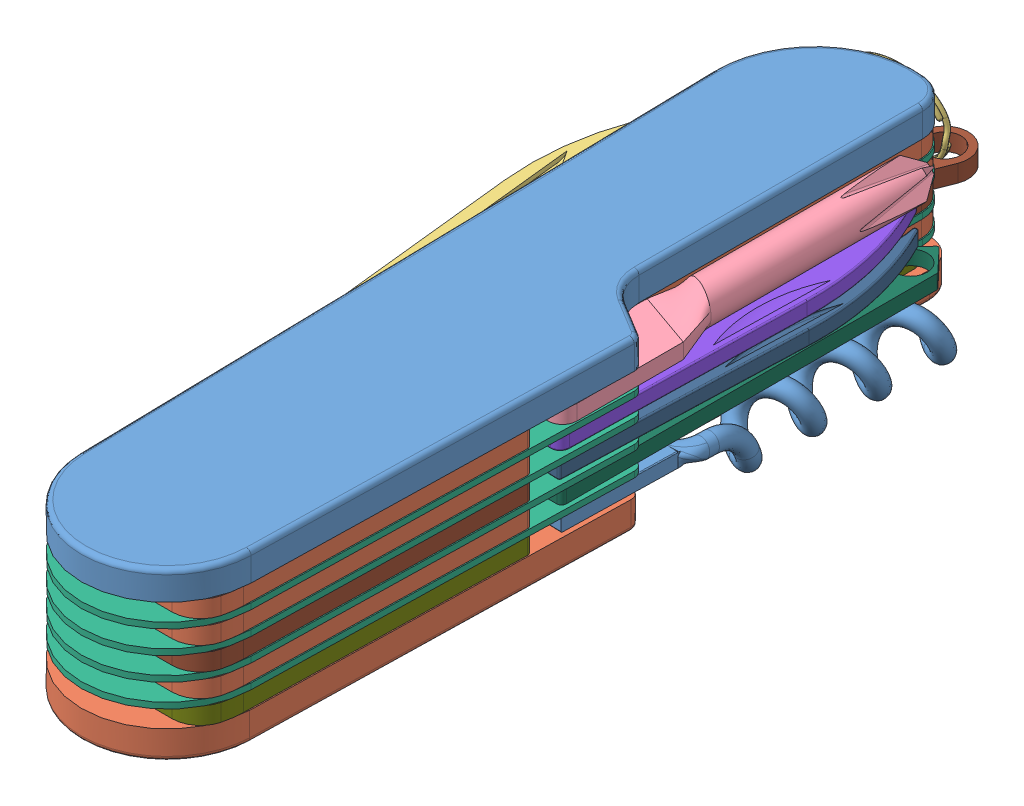
SolidWorks assembly PocketKnifeAssem, configuration Default. Lengths in mm.
Overall size (29.23 19.28 92.52).
29 component instances, 21 part files, 73 mates.
Components (placement in the parent):
- cover-1: cover [Default] at (42.4795 -100.7899 21.8266) size (20.34 3 87.48)
- small_plate2-1: small_plate2 [Default] at (33.7389 -100.7899 -56.4961) x (1 0 0) z (0 -1 0) size (18.24 83.5 1.8)
- BigKnife-1: BigKnife [Default] at (33.6183 -101.5899 24.7252) x (0.994522 0 -0.104528) z (0 1 0) size (12.5 72.88 1.71)
- philips-1: philips [Default] at (49.8425 -100.3899 -50.8894) x (0 0 1) z (-1 0 0) size (41 4.02 5.91)
- pin-1: pin [Default] at (49.2494 -106.6899 -13.3894) x (0.810621 0 0.585571) z (0 -1 0) size (2 2 15.8)
- pin-2: pin [Default] at (39.7745 -106.6899 20.1566) x (0.663596 0 -0.748091) z (0 -1 0) size (2 2 15.8)
- pin-3: pin [Default] at (37.0805 -106.6899 -47.79) x (0.663596 0 -0.748091) z (0 -1 0) size (2 2 15.8)
- plateyall-1: plateyall [Default] at (42.4795 -103.2149 21.8266) size (20.34 0.62 87.48)
- saw-1: saw [Default] at (33.7111 -104.8149 24.7649) x (0.991886 0 -0.12713) z (0.12713 0 0.991886) size (11.09 3.22 73.69)
- reamer -1: reamer  [Default] at (45.7749 -103.2149 -10.0144) x (0.021815 0 -0.999762) z (0 -1 0) size (40.75 6.2 2.29)
- small_plate2-3: small_plate2 [Default] at (33.7389 -103.2149 -56.4961) x (1 0 0) z (0 -1 0) size (18.24 83.5 1.8)
- sawknife-1: sawknife [Default] at (32.0153 -107.1399 28.3905) x (0.99956 0 -0.029666) z (0.029666 0 0.99956) size (11.83 1.5 73.8)
- NailPolisher -1: NailPolisher  [Default] at (45.932 -105.6399 -10.0832) x (0.034899 0 -0.999391) z (0 -1 0) size (40.08 6.02 1.67)
- plateyall-2: plateyall [Default] at (42.4795 -105.6399 21.8266) size (20.34 0.62 87.48)
- plateyall-3: plateyall [Default] at (42.4795 -108.0649 21.8266) size (20.34 0.62 87.48)
- small_plate2-5: small_plate2 [Default] at (33.7389 -108.0649 -56.4961) x (1 0 0) z (0 -1 0) size (18.24 83.5 1.8)
- small_plate3-1: small_plate3 [Default] at (33.7389 -105.6399 -56.4961) x (1 0 0) z (0 -1 0) size (18.24 88.5 1.8)
- scissors-1: scissors [Default] at (33.6478 -108.8649 24.7079) x (0.996195 0 -0.087156) z (0.087156 0 0.996195) size (17.57 1.82 73.9)
  - scissors1-1: scissors1 [Default] at origin size (12.84 1.82 73.9)
  - tensed_spring-1: tensed_spring [Default] at (15.3791 -0.8 -13.3543) x (0.992407 0 -0.123) z (0 1 0) size (4.32 13.19 1.6)
  - scissor arm2-1: scissor arm2 [Default] at (15.5396 -0.8 -22.5845) x (0.985924 0 -0.167194) z (0.167194 0 0.985924) size (9 1.6 52)
- bender-1: bender [Default] at (46.0494 -108.0649 -9.9894) x (0 0 -1) z (0 -1 0) size (41.91 6 1.5)
- plateyall-4: plateyall [Default] at (42.4795 -110.4899 21.8266) size (20.34 0.62 87.48)
- small_plate1-1: small_plate1 [Default] at (33.7389 -110.4899 -56.4961) x (1 0 0) z (0 -1 0) size (8.24 80.41 1.8)
- BottleOpener-1: BottleOpener [Default] at (29.3171 -110.4899 -52.687) x (0.998732 0 0.050339) z (0.050339 0 -0.998732) size (15.07 1.63 37)
- CanOpener-1: CanOpener [Default] at (33.9411 -112.0899 24.8773) x (0.987688 0 -0.156434) z (0.156434 0 0.987688) size (12.6 3.13 35.76)
- MainBottleOpener-1: MainBottleOpener [Default] at (50.1781 -113.7399 -30.7399) x (0.999762 0 0.021815) z (-0.021815 0 0.999762) size (7.09 6.91 42)
- cover_up-1: cover_up [Default] at (42.4795 -112.2899 21.8266) x (-0.999762 0 -0.021815) z (-0.021815 0 0.999762) size (20.97 3 87.58)
- holder-1: holder [Default] at (38.6408 -104.5344 -57.3996) x (-0.031611 -0.983832 -0.176284) z (0.9843 0 -0.176502) size (10.5 1.02 10.5)
Mates (geometry in assembly coordinates):
- Coincident1: coincident: plane of cover-1 through (42.4795 -100.7899 21.8266) normal (0 -1 0); plane of small_plate2-1 through (43.3489 -100.7899 -43.9848) normal (0 1 0)
- Parallel1: parallel: plane of cover-1 through (46.3489 -97.7899 -55.9166) normal (1 0 0); plane of small_plate2-1 through (46.2389 -102.5899 -24.3461) normal (1 0 0)
- Concentric1: concentric: cylinder of cover-1 through (43.3489 -97.7899 -53.6061) axis (0 -1 0) radius 3; cylinder of small_plate2-1 through (43.3489 -102.5899 -53.6061) axis (0 1 0) radius 2.89
- Concentric2: concentric: cylinder of cover-1 through (49.2494 -98.7899 -13.3894) axis (0 -1 0) radius 1; cylinder of pin-1 through (49.2494 -114.5899 -13.3894) axis (0 1 0) radius 1
- Coincident3: coincident: plane of cover-1 through (49.2494 -98.7899 -13.3894) normal (0 -1 0); circle of pin-1
- Concentric3: concentric: cylinder of cover-1 through (39.7745 -98.7899 20.1566) axis (0 -1 0) radius 1; cylinder of pin-2 through (39.7745 -114.5899 20.1566) axis (0 1 0) radius 1
- Coincident4: coincident: plane of cover-1 through (39.7745 -98.7899 20.1566) normal (0 -1 0); plane of pin-2 through (39.7745 -98.7899 20.1566) normal (0 1 0)
- Concentric4: concentric: cylinder of cover-1 through (37.0805 -98.7899 -47.79) axis (0 -1 0) radius 1; cylinder of pin-3 through (37.0805 -114.5899 -47.79) axis (0 1 0) radius 1
- Coincident5: coincident: plane of cover-1 through (37.0805 -98.7899 -47.79) normal (0 -1 0); plane of pin-3 through (37.0805 -98.7899 -47.79) normal (0 1 0)
- Concentric5: concentric: circle of BigKnife-1; cylinder of pin-2 through (39.7745 -114.5899 20.1566) axis (0 1 0) radius 1
- Coincident6: coincident: plane of cover-1 through (42.4795 -100.7899 21.8266) normal (0 -1 0); plane of BigKnife-1 through (33.6183 -100.7899 24.7252) normal (0 1 0)
- LimitAngle1: limit planar angle = 0.10472 rad: plane of BigKnife-1 through (36.6019 -102.3968 24.4116) normal (-0.994522 0 0.104528); plane of small_plate2-1 through (43.7389 -102.5899 -41.9961) normal (-1 0 0)
- Concentric6: concentric: cylinder of philips-1 through (49.2494 -92.3899 -13.3894) axis (0 -1 0) radius 1; cylinder of pin-1 through (49.2494 -114.5899 -13.3894) axis (0 1 0) radius 1
- Coincident8: coincident: plane of cover-1 through (42.4795 -100.7899 21.8266) normal (0 -1 0); plane of philips-1 through (49.8425 -100.7899 -50.8894) normal (0 1 0)
- LimitAngle2: limit planar angle = 0 rad: plane of philips-1 through (46.3975 -100.3899 -50.8894) normal (-1 0 0); plane of small_plate2-1 through (46.2389 -102.5899 -24.3461) normal (1 0 0)
- Concentric12: concentric: cylinder of cover-1 through (43.3489 -97.7899 -53.6061) axis (0 -1 0) radius 3; cylinder of plateyall-1 through (43.3489 -102.5899 -53.6061) axis (0 -1 0) radius 3
- Coincident14: coincident: plane of small_plate2-1 through (43.3489 -102.5899 -43.9848) normal (0 -1 0); plane of plateyall-1 through (42.4795 -102.5899 21.8266) normal (0 1 0)
- Coincident16: coincident: plane of plateyall-1 through (42.4795 -103.2149 21.8266) normal (0 -1 0); plane of small_plate2-3 through (43.3489 -103.2149 -43.9848) normal (0 1 0)
- Concentric13: concentric: cylinder of small_plate2-1 through (43.3489 -102.5899 -53.6061) axis (0 1 0) radius 2.89; cylinder of small_plate2-3 through (43.3489 -105.0149 -53.6061) axis (0 1 0) radius 2.89
- Concentric14: concentric: cylinder of small_plate2-1 through (48.1532 -102.5899 24.0039) axis (0 1 0) radius 3; cylinder of small_plate2-3 through (48.1532 -105.0149 24.0039) axis (0 1 0) radius 3
- Concentric15: concentric: cylinder of pin-2 through (39.7745 -114.5899 20.1566) axis (0 1 0) radius 1; cylinder of saw-1 through (39.7745 -103.2149 20.1566) axis (0 -1 0) radius 1
- Coincident17: coincident: plane of plateyall-1 through (42.4795 -103.2149 21.8266) normal (0 -1 0); plane of saw-1 through (42.0288 -103.2149 -39.8885) normal (0 1 0)
- LimitAngle3: limit planar angle = 0.050044 rad: plane of small_plate2-3 through (43.7389 -105.0149 -41.9961) normal (-1 0 0); plane of saw-1 through (32.9483 -103.2149 18.8136) normal (-0.998748 0 0.050023)
- Concentric16: concentric: cylinder of pin-1 through (49.2494 -114.5899 -13.3894) axis (0 1 0) radius 1; cylinder of reamer -1 through (49.2494 -104.8149 -13.3894) axis (0 1 0) radius 1
- Coincident19: coincident: plane of plateyall-1 through (42.4795 -103.2149 21.8266) normal (0 -1 0); plane of reamer -1 through (22.5351 -103.2149 -35.9444) normal (0 1 0)
- LimitAngle4: limit planar angle = 3.141593 rad: plane of reamer -1 through (51.9735 -104.8149 -9.8791) normal (0.999762 0 0.021815); plane of small_plate2-3 through (51.9889 -105.0149 -6.9961) normal (0.999762 0 0.021815)
- Concentric18: concentric: cylinder of pin-3 through (37.0805 -114.5899 -47.79) axis (0 1 0) radius 1; cylinder of plateyall-2 through (37.0805 -105.0139 -47.79) axis (0 -1 0) radius 1
- Concentric19: concentric: cylinder of pin-1 through (49.2494 -114.5899 -13.3894) axis (0 1 0) radius 1; cylinder of plateyall-2 through (49.2494 -105.0139 -13.3894) axis (0 -1 0) radius 1
- Coincident22: coincident: plane of small_plate2-3 through (43.3489 -105.0149 -43.9848) normal (0 -1 0); plane of plateyall-2 through (42.4795 -105.0149 21.8266) normal (0 1 0)
- Concentric23: concentric: cylinder of pin-1 through (49.2494 -114.5899 -13.3894) axis (0 1 0) radius 1; cylinder of NailPolisher -1 through (49.2494 -105.6399 -13.3894) axis (0 -1 0) radius 1
- Coincident28: coincident: plane of NailPolisher -1 through (22.8309 -105.6399 -36.2436) normal (0 1 0); plane of plateyall-2 through (42.4795 -105.6399 21.8266) normal (0 -1 0)
- Concentric24: concentric: cylinder of pin-3 through (37.0805 -114.5899 -47.79) axis (0 1 0) radius 1; cylinder of plateyall-3 through (37.0805 -107.4389 -47.79) axis (0 -1 0) radius 1
- Concentric25: concentric: cylinder of pin-2 through (39.7745 -114.5899 20.1566) axis (0 1 0) radius 1; cylinder of plateyall-3 through (39.7745 -107.4389 20.1566) axis (0 -1 0) radius 1
- Coincident33: coincident: plane of plateyall-2 through (42.4795 -105.6399 21.8266) normal (0 -1 0); plane of small_plate3-1 through (43.3489 -105.6399 -43.9848) normal (0 1 0)
- Concentric28: concentric: cylinder of small_plate2-3 through (48.1532 -105.0149 24.0039) axis (0 1 0) radius 3; cylinder of small_plate3-1 through (48.1532 -107.4399 24.0039) axis (0 1 0) radius 3
- Concentric29: concentric: cylinder of small_plate2-3 through (43.3489 -105.0149 -53.6061) axis (0 1 0) radius 2.89; cylinder of small_plate3-1 through (43.3489 -107.4399 -53.6061) axis (0 1 0) radius 2.89
- Coincident34: coincident: plane of plateyall-3 through (42.4795 -108.0649 21.8266) normal (0 -1 0); plane of small_plate2-5 through (43.3489 -108.0649 -43.9848) normal (0 1 0)
- Concentric30: concentric: cylinder of small_plate2-5 through (48.1532 -109.8649 24.0039) axis (0 1 0) radius 3; cylinder of small_plate3-1 through (48.1532 -107.4399 24.0039) axis (0 1 0) radius 3
- LimitAngle7: limit planar angle = 0.034907 rad: plane of NailPolisher -1 through (51.9283 -107.2399 -9.8738) normal (0.999391 0 0.034899); plane of small_plate3-1 through (46.2389 -107.4399 -24.3461) normal (1 0 0)
- Concentric31: concentric: cylinder of pin-2 through (39.7745 -114.5899 20.1566) axis (0 1 0) radius 1; cylinder of sawknife-1 through (39.7745 -105.6399 20.1566) axis (0 -1 0) radius 1
- Coincident36: coincident: plane of sawknife-1 through (32.0153 -105.6399 28.3905) normal (0 1 0); plane of plateyall-2 through (42.4795 -105.6399 21.8266) normal (0 -1 0)
- LimitAngle9: limit planar angle = 0.029671 rad: plane of sawknife-1 through (35.7714 -107.2399 13.3724) normal (-0.99956 0 0.029666); plane of small_plate3-1 through (43.7389 -107.4399 -41.9961) normal (-1 0 0)
- Concentric32: concentric: cylinder of pin-2 through (39.7745 -114.5899 20.1566) axis (0 1 0) radius 1; cylinder of scissors-1/scissors1-1 through (39.7745 -109.6649 20.1566) axis (0 1 0) radius 1
- Coincident38: coincident: plane of plateyall-3 through (42.4795 -108.0649 21.8266) normal (0 -1 0); plane of scissors-1/scissors1-1 through (33.7494 -108.0649 -15.5676) normal (0 1 0)
- Concentric33: concentric: cylinder of small_plate2-3 through (43.3489 -105.0149 -53.6061) axis (0 1 0) radius 2.89; cylinder of small_plate2-5 through (43.3489 -109.8649 -53.6061) axis (0 1 0) radius 2.89
- LimitAngle10: limit planar angle = 0.087266 rad: plane of small_plate2-5 through (43.7389 -109.8649 -41.9961) normal (-1 0 0); plane of scissors-1/scissors1-1 through (36.6364 -109.6649 24.4465) normal (-0.996195 0 0.087156)
- Concentric34: concentric: cylinder of pin-1 through (49.2494 -114.5899 -13.3894) axis (0 1 0) radius 1; cylinder of bender-1 through (49.2494 -108.0649 -13.3894) axis (0 -1 0) radius 1
- Coincident43: coincident: plane of plateyall-3 through (42.4795 -108.0649 21.8266) normal (0 -1 0); plane of bender-1 through (46.0494 -108.0649 -9.9894) normal (0 1 0)
- LimitAngle11: limit planar angle = 0 rad: plane of bender-1 through (52.0494 -109.5649 -9.9894) normal (1 0 0); plane of small_plate2-5 through (46.2389 -109.8649 -24.3461) normal (1 0 0)
- Concentric35: concentric: cylinder of pin-2 through (39.7745 -114.5899 20.1566) axis (0 1 0) radius 1; cylinder of plateyall-4 through (39.7745 -109.8639 20.1566) axis (0 -1 0) radius 1
- Concentric36: concentric: cylinder of pin-3 through (37.0805 -114.5899 -47.79) axis (0 1 0) radius 1; circle of plateyall-4
- Coincident46: coincident: plane of small_plate2-5 through (43.3489 -109.8649 -43.9848) normal (0 -1 0); plane of plateyall-4 through (42.4795 -109.8649 21.8266) normal (0 1 0)
- Concentric37: concentric: cylinder of pin-1 through (49.2494 -114.5899 -13.3894) axis (0 1 0) radius 1; cylinder of MainBottleOpener-1 through (49.2494 -117.0391 -13.3894) axis (0 1 0) radius 1
- Coincident47: coincident: plane of plateyall-4 through (42.4795 -110.4899 21.8266) normal (0 -1 0); plane of MainBottleOpener-1 through (50.1781 -110.4899 -30.7399) normal (0 1 0)
- Coincident48: coincident: plane of plateyall-4 through (42.4795 -110.4899 21.8266) normal (0 -1 0); plane of small_plate1-1 through (43.3489 -110.4899 -43.9848) normal (0 1 0)
- Concentric38: concentric: cylinder of small_plate2-5 through (48.1532 -109.8649 24.0039) axis (0 1 0) radius 3; cylinder of small_plate1-1 through (48.1532 -112.2899 24.0039) axis (0 1 0) radius 3
- Parallel16: parallel: plane of small_plate2-5 through (51.9889 -109.8649 -6.9961) normal (0.999762 0 0.021815); plane of small_plate1-1 through (51.9889 -112.2899 -6.9961) normal (0.999762 0 0.021815)
- Concentric39: concentric: cylinder of pin-2 through (39.7745 -114.5899 20.1566) axis (0 1 0) radius 1; cylinder of CanOpener-1 through (39.7745 -112.0899 20.1566) axis (0 1 0) radius 1
- Coincident50: coincident: plane of plateyall-4 through (42.4795 -110.4899 21.8266) normal (0 -1 0); plane of CanOpener-1 through (46.5346 -110.4899 1.9247) normal (0 1 0)
- LimitAngle12: limit planar angle = 2.984513 rad: plane of CanOpener-1 through (33.9411 -110.4899 24.8773) normal (-0.987688 0 0.156434); plane of small_plate1-1 through (43.7389 -112.2899 -41.9961) normal (-1 0 0)
- LimitAngle13: limit planar angle = 3.141593 rad: plane of MainBottleOpener-1 through (52.2385 -111.9899 -22.0262) normal (0.999762 0 0.021815); plane of small_plate1-1 through (51.9889 -112.2899 -6.9961) normal (0.999762 0 0.021815)
- Concentric40: concentric: cylinder of pin-3 through (37.0805 -114.5899 -47.79) axis (0 1 0) radius 1; cylinder of BottleOpener-1 through (37.0805 -110.4899 -47.79) axis (0 -1 0) radius 1
- Coincident54: coincident: plane of small_plate1-1 through (43.3489 -112.2899 -43.9848) normal (0 -1 0); plane of cover_up-1 through (42.5731 -112.2899 -46.1875) normal (0 1 0)
- Concentric41: concentric: cylinder of cover-1 through (42.4795 -97.7899 21.8266) axis (0 -1 0) radius 9; cylinder of cover_up-1 through (42.4795 -115.2899 21.8266) axis (0 1 0) radius 9
- Parallel17: parallel: cylinder of cover-1 through (42.4795 -97.7899 -46.1734) axis (0 -1 0) radius 10.4834; cylinder of cover_up-1 through (42.5731 -115.2899 -46.1875) axis (0 1 0) radius 10.5773
- Coincident55: coincident: plane of plateyall-3 through (42.4795 -107.4399 21.8266) normal (0 1 0); plane of small_plate3-1 through (43.3489 -107.4399 -43.9848) normal (0 -1 0)
- Parallel19: parallel: plane of cover-1 through (33.4817 -97.7899 22.023) normal (-0.999762 0 0.021815); plane of cover_up-1 through (33.4817 -115.2899 22.023) normal (-0.999762 0 0.021815)
- Concentric46: concentric: cylinder of small_plate3-1 through (43.2389 -107.4399 -58.9957) axis (0 1 0) radius 1.75; point of holder-1
- Concentric50: concentric: cylinder of small_plate3-1 through (43.2389 -107.4399 -58.9957) axis (0 1 0) radius 1.75; point of holder-1
- LimitDistance3: limit distance = 103 mm: point of holder-1; plane of assembly
- LimitAngle16: limit planar angle = 1.745329 rad: plane of assembly through (0 0 0) normal (1 0 0); plane of holder-1 through (38.5939 -104.4861 -57.6611) normal (-0.173648 0.179096 -0.968386)
- Coincident56: coincident: plane of plateyall-4 through (42.4795 -110.4899 21.8266) normal (0 -1 0); plane of BottleOpener-1 through (42.4068 -110.4899 -37.7591) normal (0 1 0)
- LimitAngle18: limit planar angle = 3.091232 rad: plane of small_plate1-1 through (43.7389 -112.2899 -41.9961) normal (-1 0 0); plane of BottleOpener-1 through (31.814 -110.4899 -52.5611) normal (-0.998732 0 -0.050339)
